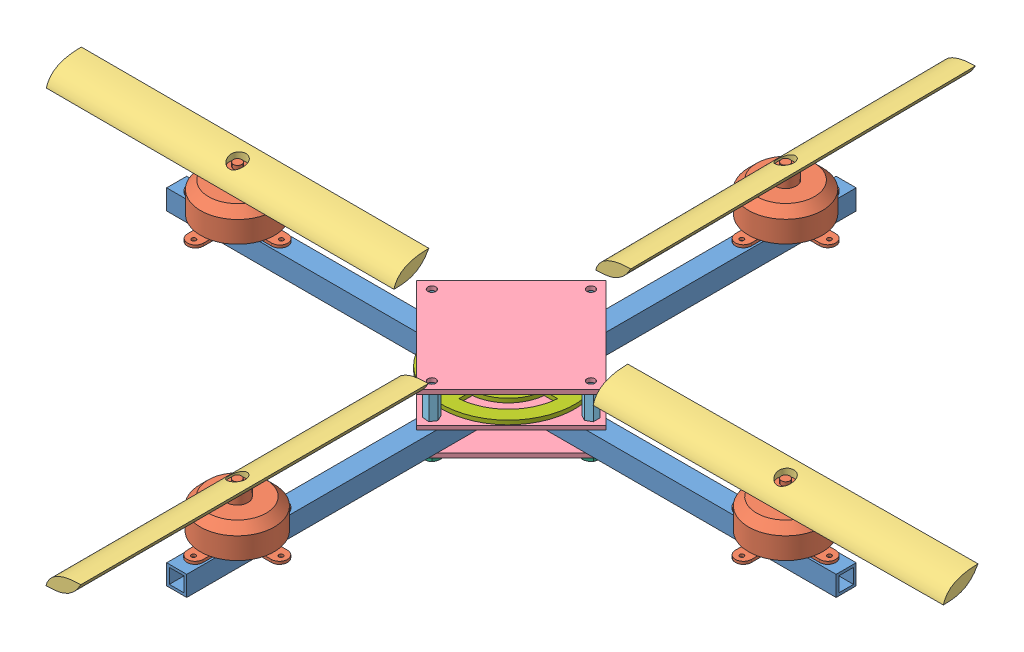
SolidWorks assembly structure_quadcopter, configuration Défaut. Lengths in mm.
Overall size (334.68 30.38 334.82).
22 component instances, 7 part files, 47 mates.
Components (placement in the parent):
- profilé alu-1: profilé alu [Défaut] at (72.4271 -14.5959 -22.4506) size (7.5 7.5 250)
- profilé alu-2: profilé alu [Défaut] at (156.4615 8.7087 61.5838) x (0 0 -1) z (-1 0 0) size (7.5 7.5 250)
- MOTEUR-1: MOTEUR [Défaut] at (73.1003 0.8064 8.3842) x (1 0 0) z (0 1 0) size (37.5 37.5 17.85)
- MOTEUR-2: MOTEUR [Défaut] at (-29.1498 0.8064 110.7612) x (1 0 0) z (0 1 0) size (37.5 37.5 17.85)
- MOTEUR-3: MOTEUR [Défaut] at (73.1003 0.8064 213.1383) x (1 0 0) z (0 1 0) size (37.5 37.5 17.85)
- MOTEUR-4: MOTEUR [Défaut] at (175.4773 0.8064 110.7612) x (1 0 0) z (0 1 0) size (37.5 37.5 17.85)
- hélice-1: hélice [Défaut] at (31.4616 13.2564 0.1723) x (0.009876 0 0.999951) z (-0.999951 0 0.009876) size (130 7.08 13)
- hélice-2: hélice [Défaut] at (31.4616 13.2564 204.9264) x (0.001274 0 0.999999) z (-0.999999 0 0.001274) size (130 7.08 13)
- hélice-3: hélice [Défaut] at (-70.7885 13.2564 102.5493) x (0.999999 0 0.00159) z (-0.00159 0 0.999999) size (130 7.08 13)
- hélice-4: hélice [Défaut] at (133.8386 13.2564 102.5493) x (0.999981 0 -0.006177) z (0.006177 0 0.999981) size (130 7.08 13)
- support-2: support [Défaut] at (31.9137 0.8064 114.6682) x (0.707107 0 -0.707107) z (0 1 0) size (50 50 1.5)
- support-3: support [Défaut] at (19.3426 -8.1936 103.0015) x (0.707107 0 0.707107) z (0 1 0) size (50 50 1.5)
- colonette M3_10-5: colonette M3_10 [Défaut] at (1.7631 -1.6936 102.5493) size (4.28 14 4.93)
- colonette M3_10-9: colonette M3_10 [Défaut] at (31.4616 -1.6936 72.8508) x (-0.23912 0 0.97099) z (-0.97099 0 -0.23912) size (4.28 14 4.93)
- colonette M3_10-10: colonette M3_10 [Défaut] at (31.4616 -1.6936 132.2478) x (0.901192 0 -0.433419) z (0.433419 0 0.901192) size (4.28 14 4.93)
- colonette M3_10-8: colonette M3_10 [Défaut] at (61.1601 -1.6936 102.5493) x (0.49697 0 0.867768) z (-0.867768 0 0.49697) size (4.28 14 4.93)
- support-4: support [Défaut] at (31.0094 13.8064 114.6682) x (-0.707107 0 -0.707107) z (0 -1 0) size (50 50 1.5)
- Hex Screw GradeAB_IfSO-1: Hex Screw GradeAB_IfSO [ISO 4017 - M3 x 10-N] at (31.4616 -10.2936 132.2478) x (0 1 0) z (0.969491 0 0.245128) size (9.6 6.35 5.5)
- Hex Screw GradeAB_IfSO-2: Hex Screw GradeAB_IfSO [ISO 4017 - M3 x 10-N] at (31.4616 -10.2936 72.8508) x (0 1 0) z (0 0 1) size (9.6 6.35 5.5)
- Hex Screw GradeAB_IfSO-3: Hex Screw GradeAB_IfSO [ISO 4017 - M3 x 10-N] at (61.1601 -10.2936 102.5493) x (0 1 0) z (-0.546944 0 0.837169) size (9.6 6.35 5.5)
- Hex Screw GradeAB_IfSO-4: Hex Screw GradeAB_IfSO [ISO 4017 - M3 x 10-N] at (1.7631 -10.2936 102.5493) x (0 1 0) z (-0.546944 0 0.837169) size (9.6 6.35 5.5)
- distrib alim-1: distrib alim [Défaut] at (30.7235 2.3064 102.9943) size (50 1.5 50)
Mates (geometry in assembly coordinates):
- Coïncidente7: coincident anti-aligned: line of profilé alu-1 through (27.7116 -6.6936 -22.4507) axis (0 0 1); line of profilé alu-2 through (27.7116 -6.6936 106.2993) axis (0 0 -1)
- Coïncidente8: coincident: line of profilé alu-1 through (28.7116 -2.9436 98.7993) axis (-1 0 0); moEndPointRef_w of profilé alu-2
- Coïncidente9: coincident: plane of profilé alu-1 through (27.7116 0.8064 -22.4507) normal (0 1 0); plane of MOTEUR-1 through (34.4616 0.8064 -15.5777) normal (0 -1 0)
- Coïncidente10: coincident: plane of profilé alu-2 through (156.4616 0.8064 106.2993) normal (0 1 0); plane of MOTEUR-2 through (-67.7885 0.8064 86.7993) normal (0 -1 0)
- Coïncidente11: coincident: plane of profilé alu-2 through (156.4616 0.8064 106.2993) normal (0 1 0); plane of MOTEUR-4 through (136.8386 0.8064 86.7993) normal (0 -1 0)
- Coïncidente12: coincident: plane of profilé alu-1 through (27.7116 0.8064 -22.4507) normal (0 1 0); plane of MOTEUR-3 through (34.4616 0.8064 189.1764) normal (0 -1 0)
- Coaxiale3: concentric: circle of MOTEUR-1; circle of hélice-1
- Coaxiale4: concentric: circle of MOTEUR-3; circle of hélice-2
- Coaxiale5: concentric: circle of MOTEUR-4; circle of hélice-4
- Coaxiale6: concentric: circle of MOTEUR-2; circle of hélice-3
- Coïncidente18: coincident: plane of profilé alu-2 through (156.4616 0.8064 106.2993) normal (0 1 0); plane of MOTEUR-4 through (136.8386 0.8064 86.7993) normal (0 -1 0)
- Distance3: distance = 1.25 mm: line of MOTEUR-2 through (-57.3186 1.8064 105.5493) axis (1 0 0); line of profilé alu-2 through (156.4616 0.8064 106.2993) axis (-1 0 0)
- Distance4: distance = 4 mm: moEndPointRef_w of MOTEUR-2; moEndPointRef_w of profilé alu-2
- Distance6: distance = 1.25 mm: line of MOTEUR-1 through (28.4616 1.8064 -15.5777) axis (0 0 1); line of profilé alu-1 through (27.7116 0.8064 -22.4507) axis (0 0 1)
- Distance7: distance = 4 mm: moEndPointRef_w of MOTEUR-1; line of profilé alu-1 through (35.2116 0.8064 -22.4507) axis (-1 0 0)
- Distance8: distance = 1.25 mm: line of MOTEUR-4 through (147.3086 1.8064 105.5493) axis (1 0 0); line of profilé alu-2 through (156.4616 0.8064 106.2993) axis (-1 0 0)
- Distance9: distance = 4 mm: moEndPointRef_w of profilé alu-2; moEndPointRef_w of MOTEUR-4
- Distance10: distance = 1.25 mm: line of MOTEUR-3 through (28.4616 1.8064 218.3964) axis (0 0 1); line of profilé alu-1 through (27.7116 0.8064 106.2993) axis (0 0 1)
- Distance11: distance = 4 mm: moEndPointRef_w of profilé alu-1; moEndPointRef_w of MOTEUR-3
- Coïncidente19: coincident: plane of MOTEUR-2 through (-70.7885 17.1564 102.5493) normal (0 1 0); plane of hélice-3 through (-70.7885 17.1564 102.5493) normal (0 -1 0)
- Coïncidente20: coincident: plane of hélice-1 through (31.4616 17.1564 0.1723) normal (0 -1 0); plane of MOTEUR-1 through (31.4616 17.1564 0.1723) normal (0 1 0)
- Coïncidente21: coincident: plane of MOTEUR-4 through (133.8386 17.1564 102.5493) normal (0 1 0); plane of hélice-4 through (133.8386 17.1564 102.5493) normal (0 -1 0)
- Coïncidente22: coincident: plane of MOTEUR-3 through (31.4616 17.1564 204.9264) normal (0 1 0); plane of hélice-2 through (31.4616 17.1564 204.9264) normal (0 -1 0)
- Coïncidente32: coincident: plane of profilé alu-2 through (156.4616 0.8064 106.2993) normal (0 1 0); plane of support-2 through (31.4616 0.8064 137.9046) normal (0 -1 0)
- Angle3: planar angle = 0.785398 rad: line of support-2 through (66.8169 2.3064 102.5493) axis (-0.707107 0 -0.707107); line of profilé alu-2 through (156.4616 0.8064 106.2993) axis (-1 0 0)
- Distance15: distance = 3.75 mm: line of profilé alu-2 through (156.4616 0.8064 106.2993) axis (-1 0 0); point of support-2
- Distance16: distance = 3.75 mm: point of support-2; line of profilé alu-1 through (35.2116 0.8064 -22.4507) axis (0 0 1)
- Coïncidente38: coincident: plane of profilé alu-1 through (27.7116 -6.6936 -22.4507) normal (0 -1 0); plane of support-3 through (-3.8938 -6.6936 102.5493) normal (0 1 0)
- Angle4: planar angle = 0.785398 rad: line of support-3 through (-3.8938 -8.1936 102.5493) axis (0.707107 0 0.707107); line of profilé alu-1 through (27.7116 -6.6936 -22.4507) axis (0 0 1)
- Distance17: distance = 3.75 mm: point of support-3; line of profilé alu-2 through (27.7116 -6.6936 106.2993) axis (-1 0 0)
- Distance19: distance = 3.75 mm: point of support-3; line of profilé alu-1 through (35.2116 -6.6936 -22.4507) axis (0 0 1)
- Coaxiale7: concentric: circle of support-2; cylinder of colonette M3_10-8 through (61.1601 8.3064 102.5493) axis (0 1 0) radius 1.5
- Coïncidente45: coincident: plane of support-2 through (31.4616 2.3064 137.9046) normal (0 1 0); plane of colonette M3_10-8 through (61.1768 2.3064 100.083) normal (0 -1 0)
- Coïncidente46: coincident: circle of support-2; cylinder of colonette M3_10-10 through (31.4616 8.3064 132.2478) axis (0 1 0) radius 1.5
- Coïncidente47: coincident: plane of support-2 through (31.4616 2.3064 137.9046) normal (0 1 0); plane of colonette M3_10-10 through (29.0028 2.3064 132.0541) normal (0 -1 0)
- Coïncidente48: coincident: circle of support-2; cylinder of colonette M3_10-9 through (31.4616 8.3064 72.8508) axis (0 1 0) radius 1.5
- Coïncidente49: coincident: plane of support-2 through (31.4616 2.3064 137.9046) normal (0 1 0); plane of colonette M3_10-9 through (33.1756 2.3064 71.0774) normal (0 -1 0)
- Coaxiale8: concentric: circle of support-2; cylinder of colonette M3_10-5 through (1.7631 8.3064 102.5493) axis (0 1 0) radius 1.5
- Coïncidente51: coincident: plane of support-2 through (31.4616 2.3064 137.9046) normal (0 1 0); plane of colonette M3_10-5 through (-0.3688 2.3064 101.3091) normal (0 -1 0)
- Coïncidente52: coincident: circle of colonette M3_10-9; circle of support-4
- Coïncidente53: coincident: circle of colonette M3_10-10; circle of support-4
- Coaxiale9: concentric: circle of support-3; circle of Hex Screw GradeAB_IfSO-1
- Coïncidente54: coincident: circle of support-3; circle of Hex Screw GradeAB_IfSO-1
- Coïncidente55: coincident: circle of support-3; circle of Hex Screw GradeAB_IfSO-4
- Coïncidente56: coincident: circle of support-3; circle of Hex Screw GradeAB_IfSO-3
- Coïncidente57: coincident: circle of support-3; circle of Hex Screw GradeAB_IfSO-2
- Coïncidente58: coincident: plane of support-2 through (31.4616 2.3064 137.9046) normal (0 1 0); plane of distrib alim-1 through (-24.4179 2.3064 102.9943) normal (0 -1 0); unknown of MOTEUR-2; unknown of MOTEUR-2; unknown of MOTEUR-2; unknown of MOTEUR-2; unknown of MOTEUR-4; unknown of MOTEUR-4; unknown of MOTEUR-4; unknown of MOTEUR-4; sketch_entity of support-2; unknown of support-2; unknown of support-2; unknown of support-2
